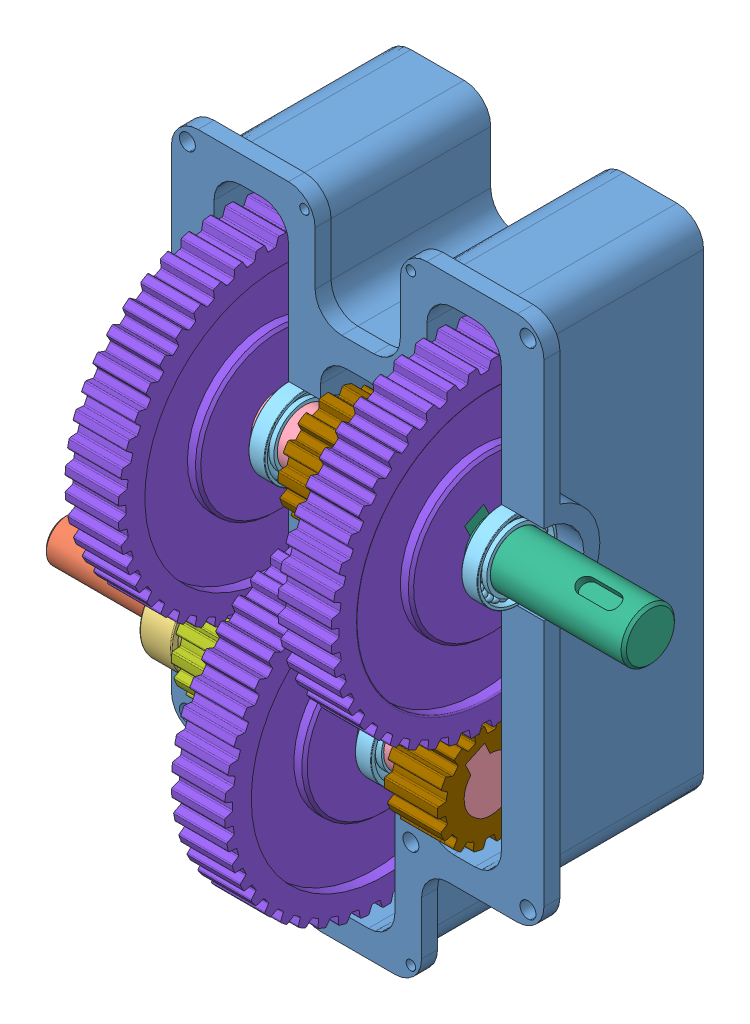
SolidWorks assembly Gear speed reducer, configuration Default. Lengths in mm.
Overall size (110 121.41 84.8).
15 component instances, 9 part files, 38 mates.
Components (placement in the parent):
- Body-1: Body [Default] at (57.1313 64.3364 83.1159) size (70 119 35)
- Input_shaft-1: Input_shaft [Default] at (2.1313 44.8364 118.1159) x (0 0.555946 0.831218) z (1 0 0) size (8.74 9 40)
- radial ball bearing_68_as-1: radial ball bearing_68_as [AS_ISO 15 RBB - 388 - 12,DE,NC,12_68] at (27.1313 44.8364 118.1159) x (-1 0 0) z (0 0 -1) size (6 16 16)
- Speed shaft-1: Speed shaft [Default] at (62.1313 83.8364 118.1159) x (0 0.722404 -0.691471) z (-1 0 0) size (10.23 12.11 30)
- angular contact ball bearing_68_as-1: angular contact ball bearing_68_as [AS_ISO 15 ABB - 1710 - 20,SI,NC,20_68] at (45.6313 83.8364 118.1159) x (-1 0 0) z (0 -0.879685 -0.475556) size (3 15 15)
- Speed shaft-2: Speed shaft [Default] at (82.1313 44.8364 118.1159) x (0 -0.420855 0.907128) z (-1 0 0) size (10.23 12.11 30)
- angular contact ball bearing_68_as-2: angular contact ball bearing_68_as [AS_ISO 15 ABB - 1710 - 20,SI,NC,20_68] at (65.6313 44.8364 118.1159) size (3 15 15)
- Output Shaft-1: Output Shaft [Default] at (72.1313 83.8364 118.1159) x (0 0.443483 -0.896283) z (1 0 0) size (10 12 40)
- angular contact ball bearing_68_as-3: angular contact ball bearing_68_as [AS_ISO 15 ABB - 1710 - Full,DE,NC,Full_68] at (85.6313 83.8364 118.1159) x (-1 0 0) z (0 -0.924225 -0.381849) size (3 15 15)
- Input Gear-1: Input Gear [Default] at (42.1313 44.8364 118.1159) x (0 -0.962332 0.271876) z (-1 0 0) size (20 19.78 10)
- Output Gear-1: Output Gear [Default] at (37.1313 83.8364 118.1159) x (0 -0.722404 0.691471) z (1 0 0) size (59.99 59.96 10)
- Middle Gear-1: Middle Gear [Default] at (52.1313 83.8364 118.1159) x (0 -0.722404 0.691471) z (1 0 0) size (20 19.78 10)
- Output Gear-2: Output Gear [Default] at (57.1313 44.8364 118.1159) x (0 0.420855 -0.907128) z (1 0 0) size (59.99 59.96 10)
- Output Gear-3: Output Gear [Default] at (77.1313 83.8364 118.1159) x (0 -0.443483 0.896283) z (-1 0 0) size (59.99 59.96 10)
- Middle Gear-2: Middle Gear [Default] at (72.1313 44.8364 118.1159) x (0 0.420855 -0.907128) z (1 0 0) size (20 19.78 10)
Mates (geometry in assembly coordinates):
- Concentric1: concentric aligned: cylinder of Body-1 through (30.1313 44.8364 118.1159) axis (-1 0 0) radius 8; cylinder of Input_shaft-1 through (42.1313 44.8364 118.1159) axis (-1 0 0) radius 4
- Concentric2: concentric aligned: cylinder of Input_shaft-1 through (42.1313 44.8364 118.1159) axis (-1 0 0) radius 4; cylinder of radial ball bearing_68_as-1 through (47.7688 44.8364 118.1159) axis (-1 0 0) radius 4
- Coincident2: coincident anti-aligned: plane of Body-1 through (57.1313 64.3364 118.1159) normal (0 0 1); plane of radial ball bearing_68_as-1 through (27.1313 44.8364 118.1159) normal (0 0 -1)
- Concentric4: concentric anti-aligned: cylinder of Body-1 through (50.1313 83.8364 118.1159) axis (-1 0 0) radius 7.5; cylinder of Speed shaft-1 through (32.1313 83.8364 118.1159) axis (1 0 0) radius 5.1145
- Concentric5: concentric aligned: line of Body-1 through (50.1313 83.8364 118.1159) axis (-1 0 0); cylinder of angular contact ball bearing_68_as-1 through (66.2688 83.8364 118.1159) axis (-1 0 0) radius 5
- Coincident5: coincident aligned: plane of Body-1 through (44.1313 118.8364 86.1159) normal (-1 0 0); plane of angular contact ball bearing_68_as-1 through (44.1313 87.3556 111.6062) normal (-1 0 0)
- Concentric8: concentric anti-aligned: cylinder of Body-1 through (70.1313 44.8364 118.1159) axis (-1 0 0) radius 7.5; cylinder of Speed shaft-2 through (52.1313 44.8364 118.1159) axis (1 0 0) radius 5.1145
- Concentric9: concentric aligned: cylinder of Speed shaft-2 through (52.1313 44.8364 118.1159) axis (1 0 0) radius 5.1145; cylinder of angular contact ball bearing_68_as-2 through (44.9938 44.8364 118.1159) axis (1 0 0) radius 5
- Coincident11: coincident aligned: plane of Body-1 through (64.1313 98.8364 86.1159) normal (-1 0 0); plane of angular contact ball bearing_68_as-2 through (64.1313 51.8114 118.1159) normal (-1 0 0)
- Concentric12: concentric anti-aligned: cylinder of Body-1 through (84.1313 83.8364 118.1159) axis (1 0 0) radius 7.5; cylinder of Output Shaft-1 through (82.1313 83.8364 118.1159) axis (-1 0 0) radius 5
- Concentric13: concentric aligned: cylinder of Output Shaft-1 through (82.1313 83.8364 118.1159) axis (-1 0 0) radius 5; cylinder of angular contact ball bearing_68_as-3 through (106.2688 83.8364 118.1159) axis (-1 0 0) radius 5
- Coincident15: coincident aligned: plane of Body-1 through (84.1313 118.8364 86.1159) normal (-1 0 0); plane of angular contact ball bearing_68_as-3 through (84.1313 86.6621 111.2766) normal (-1 0 0)
- Concentric14: concentric anti-aligned: cylinder of Input_shaft-1 through (42.1313 44.8364 118.1159) axis (-1 0 0) radius 4; cylinder of Input Gear-1 through (32.1313 44.8364 118.1159) axis (1 0 0) radius 4
- Coincident16: coincident anti-aligned: plane of Input_shaft-1 through (32.1313 42.5613 119.2767) normal (0 -0.555946 -0.831218); plane of Input Gear-1 through (32.1313 40.9292 120.3683) normal (0 0.555946 0.831218)
- Distance1: distance = 2 mm anti-aligned: plane of Input Gear-1 through (32.1313 44.8364 118.1159) normal (-1 0 0); plane of Body-1 through (30.1313 118.8364 86.1159) normal (1 0 0)
- Concentric15: concentric anti-aligned: cylinder of Speed shaft-1 through (32.1313 83.8364 118.1159) axis (1 0 0) radius 5.1145; cylinder of Output Gear-1 through (42.1313 83.8364 118.1159) axis (-1 0 0) radius 5
- Coincident18: coincident anti-aligned: plane of Speed shaft-1 through (32.1313 77.5513 114.442) normal (0 -0.722404 0.691471); plane of Output Gear-1 through (42.1313 77.5513 114.442) normal (0 0.722404 -0.691471)
- Distance4: distance = 2 mm anti-aligned: plane of Body-1 through (50.1313 98.8364 86.1159) normal (1 0 0); plane of Speed shaft-2 through (52.1313 44.8364 118.1159) normal (-1 0 0)
- Coincident24: coincident aligned: plane of Speed shaft-1 through (32.1313 83.8364 118.1159) normal (-1 0 0); plane of Output Gear-1 through (32.1313 83.8364 118.1159) normal (-1 0 0)
- Distance5: distance = 2 mm anti-aligned: plane of Speed shaft-1 through (62.1313 83.8364 118.1159) normal (1 0 0); plane of Body-1 through (64.1313 98.8364 86.1159) normal (-1 0 0)
- Concentric17: concentric anti-aligned: cylinder of Speed shaft-1 through (32.1313 83.8364 118.1159) axis (1 0 0) radius 5.1145; cylinder of Middle Gear-1 through (62.1313 83.8364 118.1159) axis (-1 0 0) radius 5
- Coincident26: coincident anti-aligned: plane of Speed shaft-1 through (32.1313 77.5513 114.442) normal (0 -0.722404 0.691471); plane of Middle Gear-1 through (62.1313 77.5513 114.442) normal (0 0.722404 -0.691471)
- Coincident27: coincident anti-aligned: circle of Speed shaft-1; plane of Middle Gear-1 through (62.1313 83.8364 118.1159) normal (1 0 0)
- Distance6: distance = 2 mm anti-aligned: plane of Output Shaft-1 through (72.1313 83.8364 118.1159) normal (-1 0 0); plane of Body-1 through (70.1313 118.8364 86.1159) normal (1 0 0)
- Concentric19: concentric anti-aligned: cylinder of Speed shaft-2 through (52.1313 44.8364 118.1159) axis (1 0 0) radius 5.1145; cylinder of Output Gear-2 through (62.1313 44.8364 118.1159) axis (-1 0 0) radius 5
- Coincident29: coincident aligned: plane of Speed shaft-2 through (52.1313 44.8364 118.1159) normal (-1 0 0); plane of Output Gear-2 through (52.1313 44.8364 118.1159) normal (-1 0 0)
- Coincident30: coincident anti-aligned: plane of Speed shaft-2 through (52.1313 52.0281 119.2476) normal (0 0.420855 -0.907128); plane of Output Gear-2 through (62.1313 52.0281 119.2476) normal (0 -0.420855 0.907128)
- Concentric20: concentric anti-aligned: cylinder of Output Shaft-1 through (82.1313 83.8364 118.1159) axis (-1 0 0) radius 5; cylinder of Output Gear-3 through (72.1313 83.8364 118.1159) axis (1 0 0) radius 5
- Coincident31: coincident aligned: plane of Output Shaft-1 through (72.1313 83.8364 118.1159) normal (-1 0 0); plane of Output Gear-3 through (72.1313 83.8364 118.1159) normal (-1 0 0)
- Coincident32: coincident anti-aligned: plane of Output Shaft-1 through (82.1313 90.9974 119.4277) normal (0 0.443483 -0.896283); plane of Output Gear-3 through (72.1313 90.9974 119.4277) normal (0 -0.443483 0.896283)
- Concentric21: concentric anti-aligned: cylinder of Speed shaft-2 through (52.1313 44.8364 118.1159) axis (1 0 0) radius 5.1145; cylinder of Middle Gear-2 through (82.1313 44.8364 118.1159) axis (-1 0 0) radius 5
- Coincident33: coincident anti-aligned: plane of Speed shaft-2 through (52.1313 52.0281 119.2476) normal (0 0.420855 -0.907128); plane of Middle Gear-2 through (82.1313 52.0281 119.2476) normal (0 -0.420855 0.907128)
- Coincident34: coincident aligned: plane of Speed shaft-2 through (82.1313 44.8364 118.1159) normal (1 0 0); plane of Middle Gear-2 through (82.1313 44.8364 118.1159) normal (1 0 0)
- Distance8: distance = 2 mm anti-aligned: plane of Input_shaft-1 through (42.1313 44.8364 118.1159) normal (1 0 0); plane of Body-1 through (44.1313 118.8364 86.1159) normal (-1 0 0)
- Coincident35: coincident aligned: plane of Body-1 through (30.1313 118.8364 86.1159) normal (1 0 0); plane of radial ball bearing_68_as-1 through (30.1313 51.6364 118.1159) normal (1 0 0)
- GearMate1: gear = 60 : 20 mm: cylinder of Input Gear-1 through (32.1313 44.8364 118.1159) axis (1 0 0) radius 10; cylinder of Output Gear-1 through (42.1313 83.8364 118.1159) axis (-1 0 0) radius 30
- GearMate3: gear = 60 : 20 mm: cylinder of Middle Gear-1 through (62.1313 83.8364 118.1159) axis (-1 0 0) radius 10; cylinder of Output Gear-2 through (62.1313 44.8364 118.1159) axis (-1 0 0) radius 30
- GearMate4: gear = 20 : 60 mm: cylinder of Output Gear-3 through (72.1313 83.8364 118.1159) axis (1 0 0) radius 30; cylinder of Middle Gear-2 through (82.1313 44.8364 118.1159) axis (-1 0 0) radius 10
